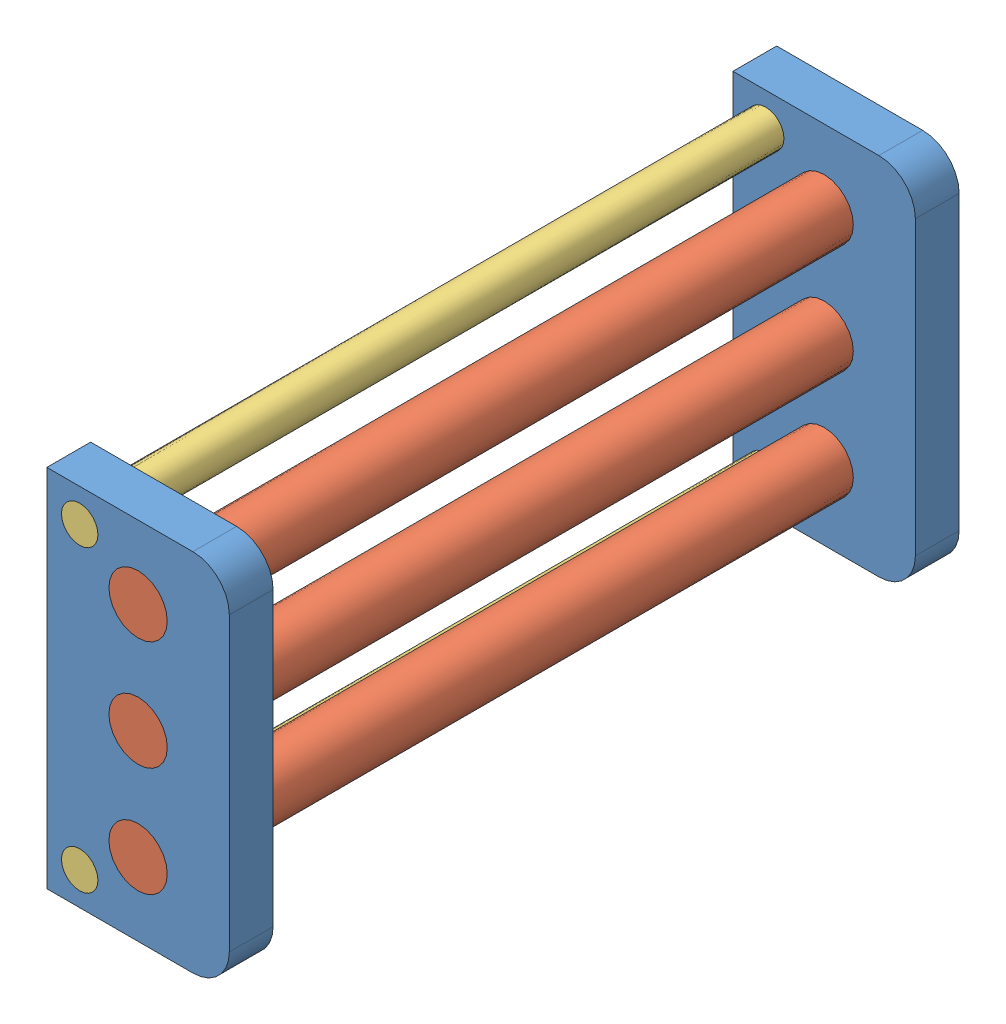
SolidWorks assembly Ensamblaje_Link3, configuration Predeterminado. Lengths in mm.
Overall size (25 50 100).
7 component instances, 3 part files, 16 mates.
Components (placement in the parent):
- Pieza1-1: Pieza1 [Predeterminado] x (0 1 0) z (1 0 0) size (50 6 25)
- Pieza5-1: Pieza5 [Predeterminado] at (0 -15 6) x (0 1 0) z (-1 0 0) size (8 100 8)
- Pieza5-2: Pieza5 [Predeterminado] at (0 15 -94) x (1 0 0) z (0 -1 0) size (8 100 8)
- Pieza9-1: Pieza9 [Predeterminado] at (-8 -20.5 6) x (1 0 0) z (0 1 0) size (5 100 5)
- Pieza9-2: Pieza9 [Predeterminado] at (-8 20.5 6) x (1 0 0) z (0 1 0) size (5 100 5)
- Pieza1-2: Pieza1 [Predeterminado] at (0 0 -94) x (0 1 0) z (1 0 0) size (50 6 25)
- Pieza5-3: Pieza5 [Predeterminado] at (0 0 6) x (1 0 0) z (0 1 0) size (8 100 8)
Mates (geometry in assembly coordinates):
- Coincidente1: coincident aligned: plane of Pieza1-1 through (0 0 0) normal (0 0 1)
- Coincidente2: coincident aligned: plane of Pieza1-1 through (0 0 0) normal (1 0 0)
- Coincidente3: coincident aligned: plane of Pieza1-1 through (0 0 0) normal (0 1 0)
- Concéntrica2: concentric anti-aligned: cylinder of Pieza1-1 through (0 -15 6) axis (0 0 -1) radius 4; cylinder of Pieza5-1 through (0 -15 -94) axis (0 0 1) radius 4
- Concéntrica3: concentric aligned: cylinder of Pieza1-1 through (0 15 6) axis (0 0 -1) radius 4; cylinder of Pieza5-2 through (0 15 6) axis (0 0 -1) radius 4
- Coincidente7: coincident aligned: plane of Pieza1-1 through (0 0 6) normal (0 0 1); plane of Pieza5-2 through (0 15 6) normal (0 0 1)
- Coincidente8: coincident aligned: plane of Pieza1-1 through (0 0 6) normal (0 0 1); plane of Pieza5-1 through (0 -15 6) normal (0 0 1)
- Concéntrica4: concentric anti-aligned: cylinder of Pieza1-1 through (-8 20.5 6) axis (0 0 -1) radius 2.5; cylinder of Pieza9-2 through (-8 20.5 -94) axis (0 0 1) radius 2.5
- Coincidente9: coincident aligned: plane of Pieza1-1 through (0 0 6) normal (0 0 1); plane of Pieza9-2 through (-8 20.5 6) normal (0 0 1)
- Concéntrica5: concentric anti-aligned: cylinder of Pieza1-1 through (-8 -20.5 6) axis (0 0 -1) radius 2.5; cylinder of Pieza9-1 through (-8 -20.5 -94) axis (0 0 1) radius 2.5
- Coincidente10: coincident aligned: plane of Pieza1-1 through (0 0 6) normal (0 0 1); plane of Pieza9-1 through (-8 -20.5 6) normal (0 0 1)
- Concéntrica6: concentric anti-aligned: cylinder of Pieza5-1 through (0 -15 -94) axis (0 0 1) radius 4; cylinder of Pieza1-2 through (0 -15 -88) axis (0 0 -1) radius 4
- Concéntrica7: concentric aligned: cylinder of Pieza5-2 through (0 15 6) axis (0 0 -1) radius 4; cylinder of Pieza1-2 through (0 15 -88) axis (0 0 -1) radius 4
- Coincidente11: coincident aligned: plane of Pieza5-2 through (0 15 -94) normal (0 0 -1); plane of Pieza1-2 through (0 0 -94) normal (0 0 -1)
- Concéntrica10: concentric anti-aligned: cylinder of Pieza1-1 through (0 0 6) axis (0 0 -1) radius 4; cylinder of Pieza5-3 through (0 0 -94) axis (0 0 1) radius 4
- Coincidente16: coincident aligned: plane of Pieza1-1 through (0 0 6) normal (0 0 1); plane of Pieza5-3 through (0 0 6) normal (0 0 1)
